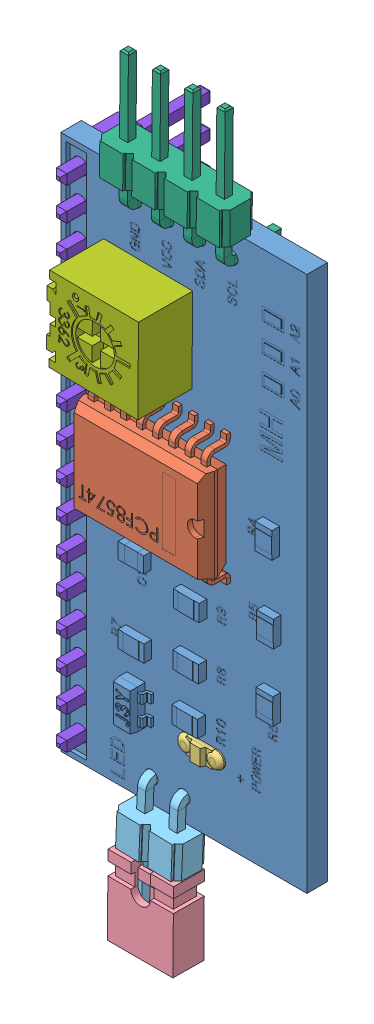
SolidWorks assembly Assembly V1, configuration Default. Lengths in mm.
Overall size (19.16 59.48 14.34).
8 component instances, 8 part files, 4 mates.
Components (placement in the parent):
- PAPAN-1: PAPAN [Default] at (11.1169 15.3214 38.5991) size (19.1 41.6 2.7)
- IC I2C-1: IC I2C [Default] at (10.1674 17.5005 41.7516) x (0 -1 0) z (-1 0 0) size (10.12 2.79 10.22)
- LED-1: LED [Default] at (12.5781 0.1232 40.1991) x (1 0 0) z (0 -1 0) size (3.53 0.6 1.27)
- ojumper 2 pin-1: ojumper 2 pin [Default] at (9.5754 -14.489 40.8581) x (1 0 0) z (0 0.999962 -0.008727) size (5.08 2.4 6.1)
- Pin Header 2 Bengkok-1: Pin Header 2 Bengkok [Default] at (10.9784 -8.1543 41.9735) x (0.000152 0.017452 0.999848) z (-0.999657 0.026174 -0.000305) size (5.52 10.82 5)
- Pin Header 4 Bengkok-1: Pin Header 4 Bengkok [Default] at (7.3535 38.9662 42.0662) x (0 0 1) z (0.999962 -0.008727 0) size (5.52 10.82 10)
- POTENSIO-1: POTENSIO [Default] at (8.2173 27.543 40.1991) x (-0.999962 0.008727 0) z (0.008727 0.999962 0) size (7.1 7.44 6.6)
- 16 pin header-1: 16 pin header [Default] at (2.7743 34.34 36.0557) x (0 -1 0) z (0 0 1) size (40.64 2.54 11.54)
Mates (geometry in assembly coordinates):
- Coincident1: coincident anti-aligned: plane of PAPAN-1 through (11.1169 15.3214 40.1991) normal (0 0 1); plane of IC I2C-1 through (5.9674 22.1614 40.1991) normal (0 0 -1)
- Parallel2: parallel anti-aligned: plane of IC I2C-1 through (5.0574 21.1255 41.9916) normal (-1 0 0); plane of PAPAN-1 through (20.6622 -5.4542 40.1991) normal (1 0 0)
- Coincident4: coincident anti-aligned: plane of PAPAN-1 through (11.1169 15.3214 40.1991) normal (0 0 1); plane of LED-1 through (13.7048 0.1189 40.1991) normal (0 0 -1)
- Coincident15: coincident anti-aligned: plane of PAPAN-1 through (11.1169 15.3214 40.1991) normal (0 0 1); plane of POTENSIO-1 through (8.2173 27.543 40.1991) normal (0 0 -1)
